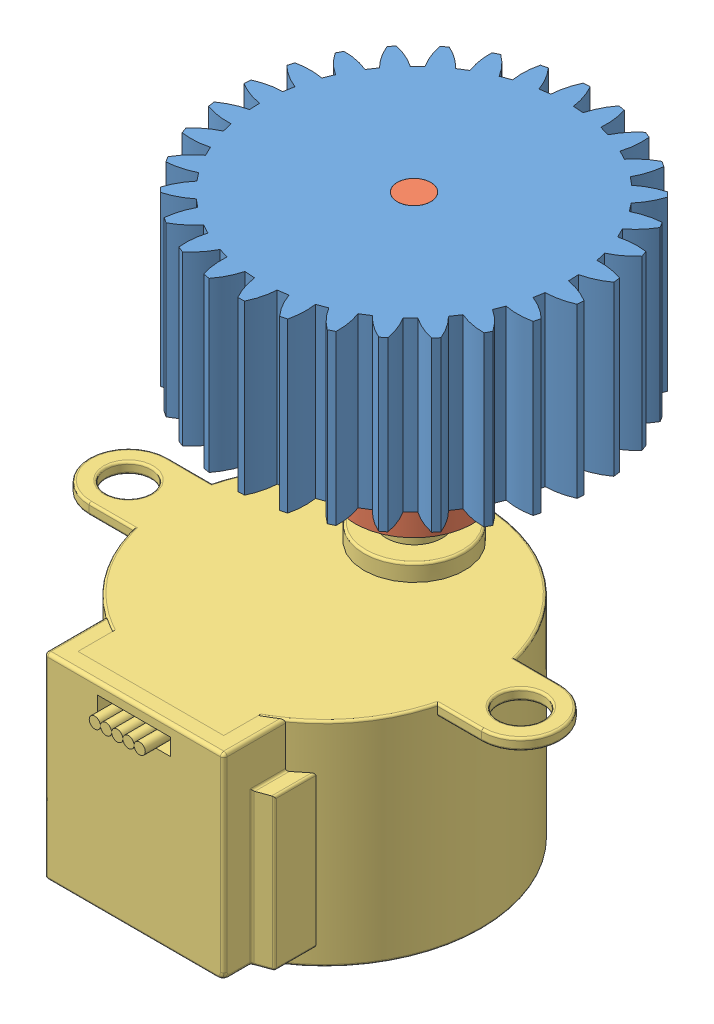
SolidWorks assembly motor_pinion assembly, configuration Default. Lengths in mm.
Overall size (42 46 46.94).
3 component instances, 3 part files, 6 mates.
Components (placement in the parent):
- spur gear_am-1: spur gear_am [Metric - Spur gear 1M 30T 20PA 15FW ---S30N75H50L3N] at (0 8 0) x (0 1 0) z (-0.939359 0 0.342936) size (15 31.88 32)
- pinion block-1: pinion block [Default] at origin size (15 29 15)
- Stepper_28BYJ-48-2: Stepper_28BYJ-48 [Default] at (0 -23 7.975) x (0 0 1) z (-1 0 0) size (32.5 29 42)
Mates (geometry in assembly coordinates):
- Concentric1: concentric aligned: cylinder of spur gear_am-1 through (0 58.0001 0) axis (0 -1 0) radius 1.5; cylinder of pinion block-1 through (0 23 0) axis (0 -1 0) radius 1.5
- Coincident1: coincident anti-aligned: plane of spur gear_am-1 through (0 8 0) normal (0 -1 0); plane of pinion block-1 through (0 8 0) normal (0 1 0)
- Coincident2: coordinate: point of pinion block-1
- Coincident3: coincident anti-aligned: plane of pinion block-1 through (0 6 0) normal (0 -1 0); plane of Stepper_28BYJ-48-2 through (0 6 -0.025) normal (0 1 0)
- Coincident4: coincident anti-aligned: plane of pinion block-1 through (-2.5 6 -1.525) normal (0 0 1); plane of Stepper_28BYJ-48-2 through (3 6 -1.525) normal (0 0 -1)
- Tangent2: tangent anti-aligned: plane of pinion block-1 through (-2.5 6 -1.525) normal (1 0 0); cylinder of Stepper_28BYJ-48-2 through (0 -2.5 -0.025) axis (0 1 0) radius 2.5
